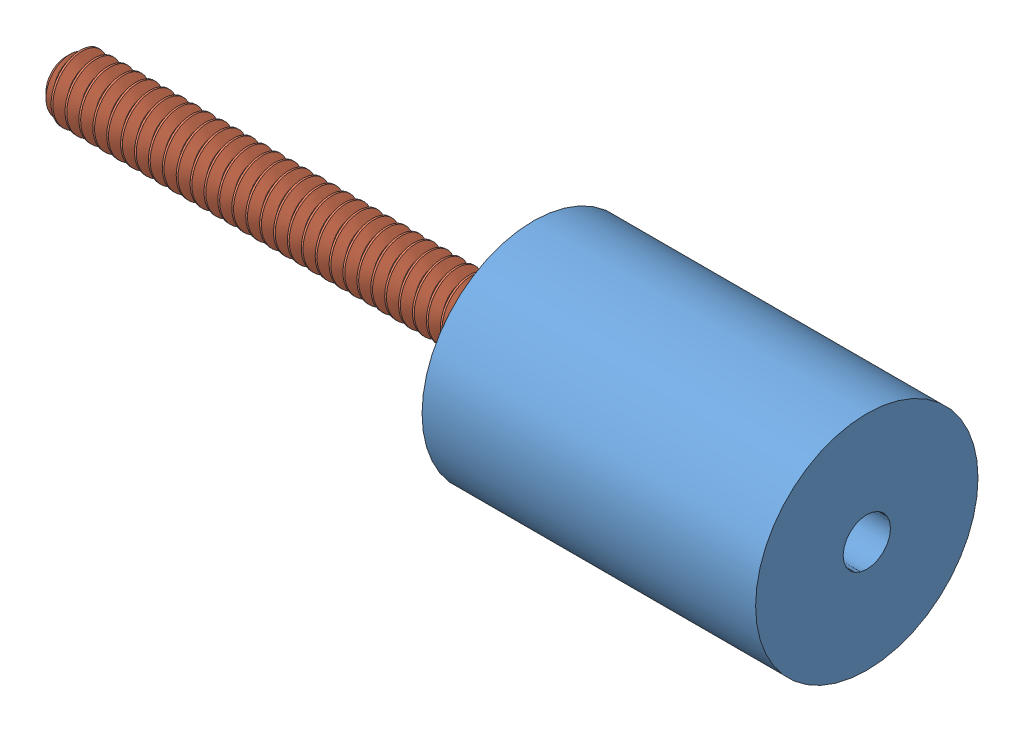
SolidWorks assembly Load cell substitute subassembly, configuration Default. Lengths in mm.
Overall size (46.17 12.7 12.7).
2 component instances, 2 part files, 2 mates.
Components (placement in the parent):
- Load cell substitute-1: Load cell substitute [Default] at (10.504 13.5898 20.6316) size (19.05 12.7 12.7)
- 6-32 Threaded rod 1.5in-1: 6-32 Threaded rod 1.5in [95412A874] at (2.884 13.5898 20.6316) size (38.99 3.54 3.7)
Mates (geometry in assembly coordinates):
- Coincident1: coincident anti-aligned: line of Load cell substitute-1 through (30.824 13.5898 20.6316) axis (-1 0 0); line of 6-32 Threaded rod 1.5in-1 through (-15.5707 13.5898 20.6316) axis (1 0 0)
- Distance1: distance = 26.67 mm aligned: plane of 6-32 Threaded rod 1.5in-1 through (-16.166 13.5898 20.6316) normal (-1 0 0); plane of Load cell substitute-1 through (10.504 13.5898 20.6316) normal (-1 0 0)
